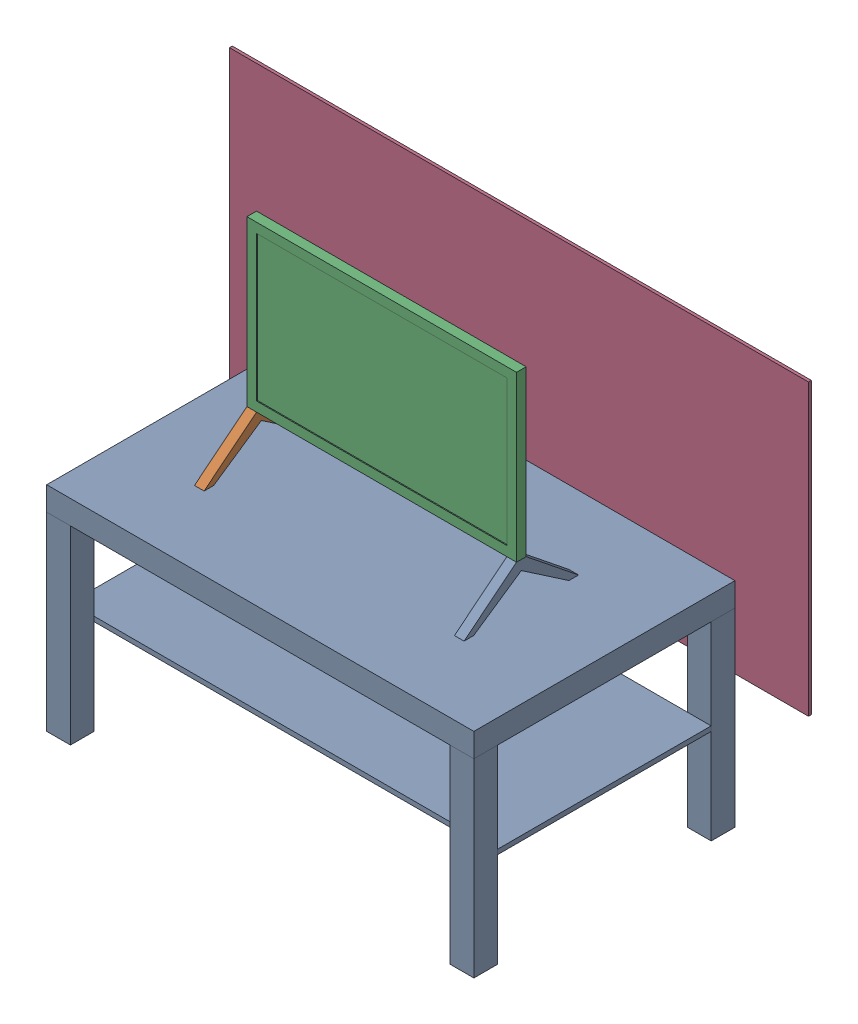
SolidWorks assembly PROJECTION-PART, configuration Défaut. Lengths in mm.
Overall size (1220 890 556).
3 component instances, 3 part files, 5 mates.
Components (placement in the parent):
- ILLUMETRY-SCREEN-1: ILLUMETRY-SCREEN [Défaut] at (280.9295 -90.9806 110.4867) size (568 435.2 241.27)
- LACK_TABLE-1: LACK_TABLE [Défaut] at (507.6591 -456.959 345.6367) size (900 450 550)
- PROJECTION_BACK-2: PROJECTION_BACK [Défaut] at (631.2295 -369.9666 -160.3633) size (1220 610 6)
Mates (geometry in assembly coordinates):
- Coïncidente1: coincident anti-aligned: plane of 250312-NIM-HEAT-ILLUMETRY-SCREEN-1 through (-246.4705 -199.9666 110.4867) normal (0 -1 0); plane of 250312-NIM-HEAT-LACK_TABLE-1 through (476.2295 -199.9666 395.6367) normal (0 1 0)
- Parallèle1: parallel anti-aligned: plane of 250312-NIM-HEAT-ILLUMETRY-SCREEN-1 through (280.9295 -90.9806 110.4867) normal (0 0 -1); plane of 250312-NIM-HEAT-PROJECTION_BACK-2 through (631.2295 -369.9666 -154.3633) normal (0 0 1)
- Coïncidente3: coincident anti-aligned: plane of 250312-NIM-HEAT-LACK_TABLE-1 through (476.2295 -199.9666 -154.3633) normal (0 0 -1); plane of 250312-NIM-HEAT-PROJECTION_BACK-2 through (631.2295 -369.9666 -154.3633) normal (0 0 1)
- Distance3: distance = 175 mm aligned: plane of 250312-NIM-HEAT-ILLUMETRY-SCREEN-1 through (301.2295 -111.2806 130.7867) normal (1 0 0); plane of 250312-NIM-HEAT-LACK_TABLE-1 through (476.2295 -199.9666 395.6367) normal (1 0 0)
- Coaxiale3: concentric anti-aligned: circle of 250312-NIM-HEAT-LACK_TABLE-1; cylinder of 250312-NIM-HEAT-PROJECTION_BACK-2 through (451.2295 -299.9666 -166.0201) axis (0 0 1) radius 2
